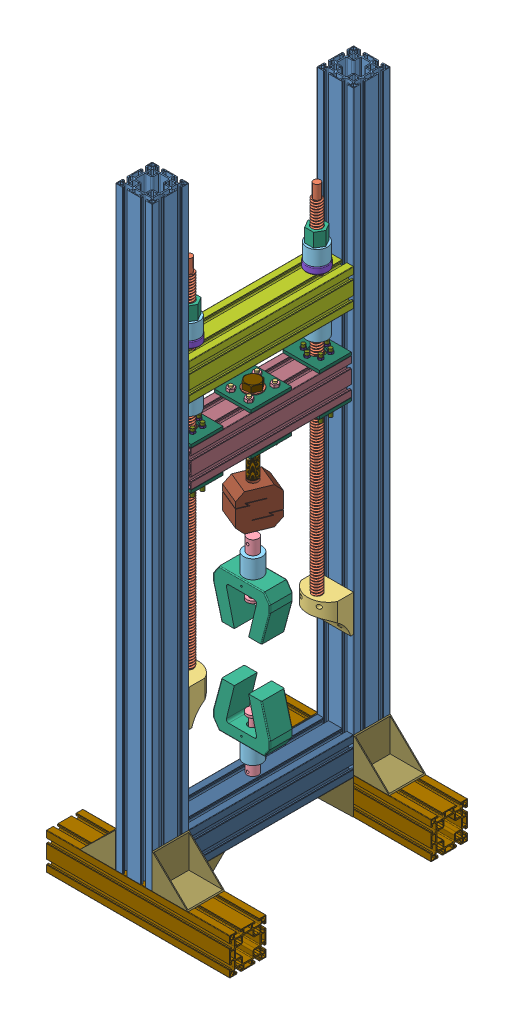
SolidWorks assembly NEWmodelUTM, configuration Default. Lengths in mm.
Overall size (400 1380 520).
55 component instances, 26 part files, 70 mates.
Components (placement in the parent):
- AL_profile780-1: AL_profile780 [Default] at (-40 0 -114.0799) size (80 1300 80)
- AL_profile780-2: AL_profile780 [Default] at (-40 0 325.9201) size (80 1300 80)
- leadscrew-1: leadscrew [Default] at (-40.1188 342.8251 -30.3753) x (0.717877 0 -0.69617) z (0 1 0) size (22.64 25.43 796)
- leadscrew-2: leadscrew [Default] at (-40.1188 342.8251 249.6247) x (0.179733 0 0.983715) z (0 1 0) size (22.64 25.43 796)
- bottomprintbase-1: bottomprintbase [Default] at (-40.1188 306.0641 289.6247) x (0 0 -1) z (1 0 0) size (60 80 80)
- Part2^NEWmodelUTM-1: Part2^NEWmodelUTM [Default] at origin (virtual)
- bottomprintbase-2: bottomprintbase [Default] at (-40.1188 306.0641 -70.3753) x (0 0 1) z (-1 0 0) size (60 80 80)
- gripper-1: gripper [Default] at (211.3531 265.4125 50.1916) x (-0.008195 0 0.999966) z (-0.999966 0 -0.008195) size (56.23 172.07 124.41)
  - grip_centre-1: grip_centre [Default] at (61.4916 134.6133 250.929) size (28.8 120.12 28.8)
  - grip_tightner-1: grip_tightner [Default] at (61.4916 140.8387 250.929) x (0.780296 0 -0.625411) z (0.625411 0 0.780296) size (40 39.84 40)
  - grip_jawbody-1: grip_jawbody [Default] at (36.4924 128.251 251.1338) x (0.999966 0 -0.008195) z (0.008195 0 0.999966) size (50 121.5 124)
- AL_profile360-1: AL_profile360 [Default] at (-40 926.1619 -70.3753) x (1 0 0) z (0 -1 0) size (80 360 80)
- ballbearing-1: ballbearing [Default] at (-40.1188 962.4573 -30.3753) x (0.823971 0 0.566631) z (-0.566631 0 0.823971) size (47.3 15 47.3)
- ballbearing-2: ballbearing [Default] at (-40.1188 962.4573 249.6247) x (0.997733 0 0.067299) z (-0.067299 0 0.997733) size (47.3 15 47.3)
- ballbearing-3: ballbearing [Default] at (-40.1188 867.4573 -30.3753) x (0.241118 0 -0.970496) z (0.970496 0 0.241118) size (47.3 15 47.3)
- ballbearing-4: ballbearing [Default] at (-40.1188 867.4573 249.6247) x (0.984243 0 0.176821) z (-0.176821 0 0.984243) size (47.3 15 47.3)
- AL_profile400legs-1: AL_profile400legs [Default] at (-231.1702 -40.1188 -114.0799) x (0 -1 0) z (0 0 1) size (80 400 80)
- AL_profile360base-1: AL_profile360base [Default] at (-40 39.3731 -70.3753) x (1 0 0) z (0 -1 0) size (80 360 80)
- AL_profile400legs-2: AL_profile400legs [Default] at (-231.1702 -43.7046 329.7436) x (0 0 1) z (0 1 0) size (80 400 80)
- gripper-2: gripper [Default] at (211.365 329.9394 169.0579) x (-0.008195 0 -0.999966) z (-0.999966 0 0.008195) size (56.23 172.07 124.41)
  - grip_centre-1: grip_centre [Default] at (61.4916 134.6133 250.929) size (28.8 120.12 28.8)
  - grip_tightner-1: grip_tightner [Default] at (61.4916 140.8387 250.929) x (0.780296 0 -0.625411) z (0.625411 0 0.780296) size (40 39.84 40)
  - grip_jawbody-1: grip_jawbody [Default] at (36.4924 128.251 251.1338) x (0.999966 0 -0.008195) z (0.008195 0 0.999966) size (50 121.5 124)
- Part3^NEWmodelUTM-1: Part3^NEWmodelUTM [Default] at origin (virtual)
- loadcell-1: loadcell [Default] at (-64.1199 589.8994 99.7422) x (0.380099 0 -0.924946) z (0.924946 0 0.380099) size (80 80 52)
- fixing brackets-1: fixing brackets [Default] at (-102.6188 22.5 -150.3753) x (0 1 0) z (1 0 0) size (75.67 80 78.01)
- fixing brackets-2: fixing brackets [Default] at (22.3812 22.5 -70.3753) x (0 1 0) z (-1 0 0) size (75.67 80 78.01)
- fixing brackets-3: fixing brackets [Default] at (22.3812 22.5 369.6247) x (0 1 0) z (-1 0 0) size (75.67 80 78.01)
- fixing brackets-4: fixing brackets [Default] at (-102.6188 22.5 289.6247) x (0 1 0) z (1 0 0) size (75.67 80 78.01)
- fixing brackets-5: fixing brackets [Default] at (-0.1188 -26.8315 -47.8753) x (0 -1 0) z (0 0 -1) size (75.67 80 78.01)
- fixing brackets-6: fixing brackets [Default] at (-80.1188 -26.8315 267.1247) x (0 -1 0) z (0 0 1) size (75.67 80 78.01)
- loading_beaM_assembly-1: loading_beaM_assembly [Default] at (-0.1307 882.4453 -65.3753) size (80.06 184 350)
  - AL_profile350-1: AL_profile350 [Default] at (-39.8812 -129.6235 350) x (1 0 0) z (0 1 0) size (80 350 80)
  - bearing for thread-1: bearing for thread [Default] at (-39.9881 -184.4189 315) size (55 44.2 55)
  - metal piece-1: metal piece [Default] at (-39.9406 -79.4189 175) x (1 0 0) z (0 -1 0) size (80 350 6.5)
  - side_threa_rods-1: side_threa_rods [Default] at (-39.9881 -199.4938 315) size (45.68 130 51.54)
  - side_threa_rods-2: side_threa_rods [Default] at (-39.9881 -199.4938 35) x (0.5 0 -0.866025) z (0.866025 0 0.5) size (45.68 130 51.54)
  - metal piece-3: metal piece [Default] at (-39.9406 -165.9189 175) x (1 0 0) z (0 -1 0) size (80 350 6.5)
  - bearing for thread-2: bearing for thread [Default] at (-39.9881 -184.4189 35) size (55 44.2 55)
  - nuts_7.8-1: nuts_7.8 [Default] at (-39.9881 -188.4189 315) size (47.17 4 54.47)
  - nuts_7.8-2: nuts_7.8 [Default] at (-39.9881 -188.4189 35) size (47.17 4 54.47)
  - nuts_7.8-3: nuts_7.8 [Default] at (-39.9881 -79.4189 35) size (47.17 4 54.47)
  - nuts_7.8-4: nuts_7.8 [Default] at (-39.9881 -79.4189 315) x (0.5 0 0.866025) z (-0.866025 0 0.5) size (47.17 4 54.47)
  - central_boltwithnut-1: central_boltwithnut [Default] at (-39.9406 -77.4189 175) x (-0.993893 0 0.11035) z (0.11035 0 0.993893) size (36.95 184 32)
  - central_nutforbolt-1: central_nutforbolt [Default] at (-39.9406 -175.2412 175) x (0.894237 0 -0.447594) z (0.447594 0 0.894237) size (41.05 18.73 38)
  - centralwaher-1: centralwaher [Default] at (-39.9406 -79.4189 175) size (40 2 40)
  - central4bolts-1: central4bolts [Default] at (-39.3156 -189.4938 174.9932) size (47.9 120 65.04)
  - M8nut-4: M8nut [Default] at (-59.8908 -79.4189 146.4879) size (55.9 6 70.85)
  - M8nut-5: M8nut [Default] at (-59.8908 -178.4189 146.4879) size (55.9 6 70.85)
- leadscrewcylindricalsupport-1: leadscrewcylindricalsupport [Default] at (-40.1188 977.4573 -30.3753) size (45 33 45)
- leadscrewcylindricalsupport-2: leadscrewcylindricalsupport [Default] at (-40.1188 977.4573 249.6247) x (0.961374 0 -0.275247) z (0.275247 0 0.961374) size (45 33 45)
- leadscrewcylindricalsupport-3: leadscrewcylindricalsupport [Default] at (-40.1188 834.4573 -30.3753) x (0.750227 0 -0.66118) z (0.66118 0 0.750227) size (45 33 45)
- leadscrewcylindricalsupport-4: leadscrewcylindricalsupport [Default] at (-40.1188 834.4573 249.6247) x (0.997856 0 -0.065451) z (0.065451 0 0.997856) size (45 33 45)
- leadscrew tightingnut-1: leadscrew tightingnut [Default] at (-40.1188 1010.4573 -30.3753) size (39.27 30 34.01)
- leadscrew tightingnut-2: leadscrew tightingnut [Default] at (-40.1188 1010.4573 249.6247) size (39.27 30 34.01)
Mates (geometry in assembly coordinates):
- Coincident1: coincident aligned: plane of AL_profile780-2 through (-80.1188 1300 325.9201) normal (-1 0 0); plane of AL_profile360-1 through (-80.1188 926.1619 289.6247) normal (-1 0 0)
- Coincident2: coincident anti-aligned: plane of AL_profile780-2 through (-40 1300 289.6247) normal (0 0 -1); plane of AL_profile360-1 through (-40 926.1619 289.6247) normal (0 0 1)
- Coincident3: coincident anti-aligned: plane of AL_profile780-1 through (-40 1300 -70.3753) normal (0 0 1); plane of AL_profile360-1 through (-40 926.1619 -70.3753) normal (0 0 -1)
- Coincident4: coincident aligned: plane of AL_profile780-1 through (-80.1188 1300 -114.0799) normal (-1 0 0); plane of AL_profile360-1 through (-80.1188 926.1619 289.6247) normal (-1 0 0)
- Coincident5: coincident anti-aligned: plane of AL_profile780-1 through (-40 1300 -70.3753) normal (0 0 1); plane of bottomprintbase-2 through (-40.1188 346.0641 -70.3753) normal (0 0 -1)
- Coincident6: coincident: plane of AL_profile780-1 through (-80.1188 1300 -114.0799) normal (-1 0 0); line of bottomprintbase-2 through (-80.1188 346.0641 -70.3753) axis (0 -1 0)
- Coincident7: coincident anti-aligned: plane of AL_profile780-2 through (-40 1300 289.6247) normal (0 0 -1); plane of bottomprintbase-1 through (-40.1188 346.0641 289.6247) normal (0 0 1)
- Coincident8: coincident aligned: plane of AL_profile780-2 through (-80.1188 1300 325.9201) normal (-1 0 0); plane of bottomprintbase-1 through (-80.1188 346.0641 289.6247) normal (-1 0 0)
- Coincident9: coincident aligned: plane of bottomprintbase-1 through (-40.1188 346.0641 289.6247) normal (0 1 0); plane of bottomprintbase-2 through (-40.1188 346.0641 -70.3753) normal (0 1 0)
- Concentric1: concentric aligned: circle of leadscrew-1; circle of AL_profile360-1
- Coincident13: coincident aligned: plane of leadscrew-1 through (-40.1188 1122.8251 -30.3753) normal (0 1 0); plane of leadscrew-2 through (-40.1188 1122.8251 249.6247) normal (0 1 0)
- Concentric2: concentric aligned: circle of leadscrew-2; circle of AL_profile360-1
- Concentric10: concentric aligned: circle of gripper-1/grip_centre-1; circle of loadcell-1
- Concentric11: concentric anti-aligned: circle of AL_profile360-1; circle of ballbearing-1
- Concentric12: concentric aligned: circle of AL_profile360-1; circle of ballbearing-2
- Concentric13: concentric aligned: circle of AL_profile360-1; circle of ballbearing-3
- Concentric14: concentric aligned: circle of AL_profile360-1; circle of ballbearing-4
- Parallel3: parallel anti-aligned: plane of AL_profile780-1 through (-80.1188 1300 -114.0799) normal (-1 0 0); plane of AL_profile400legs-1 through (168.8298 -40.1188 -114.0799) normal (1 0 0)
- Coincident22: coincident aligned: plane of AL_profile780-1 through (-40 1300 -70.3753) normal (0 0 1); plane of AL_profile400legs-1 through (168.8298 -40.1188 -70.3753) normal (0 0 1)
- Parallel4: parallel anti-aligned: plane of AL_profile400legs-1 through (168.8298 -40.1188 -70.3753) normal (0 0 1); plane of AL_profile400legs-2 through (168.8298 -43.7046 289.6247) normal (0 0 -1)
- Parallel5: parallel anti-aligned: plane of AL_profile400legs-1 through (-231.1702 -40.1188 -114.0799) normal (-1 0 0); plane of AL_profile400legs-2 through (168.8298 -43.7046 329.7436) normal (1 0 0)
- Coincident25: coincident anti-aligned: plane of AL_profile780-1 through (-40 0 -114.0799) normal (0 -1 0); plane of AL_profile400legs-1 through (168.8298 0 -114.0799) normal (0 1 0)
- Coincident27: coincident aligned: plane of AL_profile400legs-1 through (168.8298 -40.1188 -114.0799) normal (1 0 0); plane of AL_profile400legs-2 through (168.8298 -43.7046 329.7436) normal (1 0 0)
- Coincident28: coincident anti-aligned: plane of AL_profile360base-1 through (-40 39.3731 289.6247) normal (0 0 1); plane of AL_profile400legs-2 through (168.8298 -43.7046 289.6247) normal (0 0 -1)
- Coincident30: coincident anti-aligned: plane of AL_profile780-1 through (-40 1300 -70.3753) normal (0 0 1); plane of AL_profile360base-1 through (-40 39.3731 -70.3753) normal (0 0 -1)
- Coincident31: coincident aligned: plane of AL_profile780-2 through (-0.1188 1300 325.9201) normal (1 0 0); plane of AL_profile360base-1 through (-0.1188 39.3731 289.6247) normal (1 0 0)
- Concentric15: concentric anti-aligned: circle of AL_profile360base-1; circle of gripper-2/grip_centre-1
- Parallel6: parallel aligned: plane of gripper-1/grip_jawbody-1 through (-12.0328 423.7583 84.6247) normal (0 0 -1); plane of gripper-2/grip_jawbody-1 through (-12.0209 171.5936 84.6247) normal (0 0 -1)
- Coincident39: coincident anti-aligned: plane of AL_profile400legs-1 through (168.8298 0 -114.0799) normal (0 1 0); plane of fixing brackets-1 through (-80.1188 0 -70.3753) normal (0 -1 0)
- Coincident40: coincident anti-aligned: plane of AL_profile780-1 through (-80.1188 1300 -114.0799) normal (-1 0 0); plane of fixing brackets-1 through (-80.1188 0 -70.3753) normal (1 0 0)
- Coincident41: coincident aligned: plane of AL_profile780-1 through (-40 1300 -150.3753) normal (0 0 -1); plane of fixing brackets-1 through (-102.6188 22.5 -150.3753) normal (0 0 -1)
- Coincident42: coincident anti-aligned: plane of AL_profile780-1 through (-0.1188 1300 -114.0799) normal (1 0 0); plane of fixing brackets-2 through (-0.1188 0 -150.3753) normal (-1 0 0)
- Coincident43: coincident anti-aligned: plane of AL_profile400legs-1 through (168.8298 0 -114.0799) normal (0 1 0); plane of fixing brackets-2 through (-0.1188 0 -150.3753) normal (0 -1 0)
- Coincident44: coincident aligned: plane of AL_profile780-1 through (-40 1300 -150.3753) normal (0 0 -1); plane of fixing brackets-2 through (22.3812 22.5 -150.3753) normal (0 0 -1)
- Coincident45: coincident anti-aligned: plane of AL_profile780-2 through (-0.1188 1300 325.9201) normal (1 0 0); plane of fixing brackets-3 through (-0.1188 0 289.6247) normal (-1 0 0)
- Coincident46: coincident anti-aligned: plane of AL_profile400legs-2 through (168.8298 0 329.7436) normal (0 1 0); plane of fixing brackets-3 through (-0.1188 0 289.6247) normal (0 -1 0)
- Coincident47: coincident aligned: plane of AL_profile780-2 through (-40 1300 369.6247) normal (0 0 1); plane of fixing brackets-3 through (22.3812 22.5 369.6247) normal (0 0 1)
- Coincident51: coincident anti-aligned: plane of fixing brackets-4 through (-80.1188 0 369.6247) normal (0 -1 0); plane of AL_profile400legs-2 through (168.8298 0 329.7436) normal (0 1 0)
- Coincident52: coincident aligned: plane of AL_profile780-2 through (-40 1300 369.6247) normal (0 0 1); plane of fixing brackets-4 through (-102.6188 22.5 369.6247) normal (0 0 1)
- Coincident53: coincident anti-aligned: plane of AL_profile780-2 through (-80.1188 1300 325.9201) normal (-1 0 0); plane of fixing brackets-4 through (-80.1188 0 369.6247) normal (1 0 0)
- Coincident54: coincident anti-aligned: plane of AL_profile360base-1 through (-40 -4.3315 289.6247) normal (0 -1 0); plane of fixing brackets-5 through (-80.1188 -4.3315 -70.3753) normal (0 1 0)
- Coincident55: coincident anti-aligned: plane of AL_profile400legs-1 through (168.8298 -40.1188 -70.3753) normal (0 0 1); plane of fixing brackets-5 through (-80.1188 -4.3315 -70.3753) normal (0 0 -1)
- Coincident56: coincident aligned: plane of AL_profile360base-1 through (-80.1188 39.3731 289.6247) normal (-1 0 0); plane of fixing brackets-5 through (-80.1188 -26.8315 -47.8753) normal (-1 0 0)
- Coincident57: coincident anti-aligned: plane of AL_profile360base-1 through (-40 -4.3315 289.6247) normal (0 -1 0); plane of fixing brackets-6 through (-0.1188 -4.3315 289.6247) normal (0 1 0)
- Coincident58: coincident aligned: plane of AL_profile360base-1 through (-80.1188 39.3731 289.6247) normal (-1 0 0); plane of fixing brackets-6 through (-80.1188 -26.8315 267.1247) normal (-1 0 0)
- Coincident59: coincident anti-aligned: plane of AL_profile400legs-2 through (168.8298 -43.7046 289.6247) normal (0 0 -1); plane of fixing brackets-6 through (-0.1188 -4.3315 289.6247) normal (0 0 1)
- Coincident60: coincident: plane of AL_profile400legs-1 through (168.8298 -80 -114.0799) normal (0 -1 0); line of fixing brackets-5 through (-80.1188 -80 -70.3753) axis (1 0 0)
- Coincident61: coincident aligned: plane of AL_profile780-1 through (-40 1300 -114.0799) normal (0 1 0); plane of AL_profile780-2 through (-40 1300 325.9201) normal (0 1 0)
- Concentric16: concentric anti-aligned: circle of AL_profile360-1; circle of loading_beaM_assembly-1/metal piece-1
- Concentric17: concentric anti-aligned: circle of AL_profile360-1; circle of loading_beaM_assembly-1/metal piece-1
- Concentric18: concentric anti-aligned: cylinder of AL_profile360-1 through (-60.1188 902.4573 289.6247) axis (0 0 -1) radius 6.25; cylinder of AL_profile780-2 through (-60.1188 902.4573 289.6247) axis (0 0 1) radius 4
- Coincident64: coincident aligned: plane of gripper-1/grip_jawbody-1 through (-12.0328 423.7583 134.6247) normal (0 0 1); plane of gripper-2/grip_jawbody-1 through (-12.0209 171.5936 134.6247) normal (0 0 1)
- Coincident65: coincident anti-aligned: plane of AL_profile360-1 through (-40 962.4573 289.6247) normal (0 1 0); plane of ballbearing-2 through (-40.1188 962.4573 249.6247) normal (0 -1 0)
- Coincident66: coincident anti-aligned: plane of AL_profile360-1 through (-40 962.4573 289.6247) normal (0 1 0); plane of ballbearing-1 through (-40.1188 962.4573 -30.3753) normal (0 -1 0)
- Coincident67: coincident anti-aligned: plane of AL_profile360-1 through (-40 882.4573 289.6247) normal (0 -1 0); plane of ballbearing-3 through (-40.1188 882.4573 -30.3753) normal (0 1 0)
- Coincident68: coincident anti-aligned: plane of AL_profile360-1 through (-40 882.4573 289.6247) normal (0 -1 0); plane of ballbearing-4 through (-40.1188 882.4573 249.6247) normal (0 1 0)
- Concentric19: concentric aligned: circle of leadscrew-1; circle of leadscrewcylindricalsupport-1
- Coincident70: coincident anti-aligned: plane of ballbearing-1 through (-40.1188 977.4573 -30.3753) normal (0 1 0); plane of leadscrewcylindricalsupport-1 through (-40.1188 977.4573 -30.3753) normal (0 -1 0)
- Concentric21: concentric aligned: circle of leadscrew-2; circle of leadscrewcylindricalsupport-2
- Coincident71: coincident anti-aligned: plane of ballbearing-2 through (-40.1188 977.4573 249.6247) normal (0 1 0); plane of leadscrewcylindricalsupport-2 through (-40.1188 977.4573 249.6247) normal (0 -1 0)
- Concentric22: concentric aligned: circle of leadscrew-2; circle of leadscrewcylindricalsupport-4
- Concentric23: concentric aligned: circle of leadscrew-1; circle of leadscrewcylindricalsupport-3
- Coincident72: coincident aligned: plane of leadscrewcylindricalsupport-3 through (-40.1188 867.4573 -30.3753) normal (0 1 0); plane of leadscrewcylindricalsupport-4 through (-40.1188 867.4573 249.6247) normal (0 1 0)
- Coincident73: coincident anti-aligned: plane of ballbearing-3 through (-40.1188 867.4573 -30.3753) normal (0 -1 0); plane of leadscrewcylindricalsupport-3 through (-40.1188 867.4573 -30.3753) normal (0 1 0)
- Concentric24: concentric aligned: circle of leadscrew-1; circle of leadscrew tightingnut-1
- Concentric25: concentric anti-aligned: circle of leadscrew-2; cylinder of leadscrew tightingnut-2 through (-40.1188 1040.4573 249.6247) axis (0 -1 0) radius 11.5
- Coincident74: coincident aligned: plane of leadscrew tightingnut-1 through (-40.1188 1040.4573 -30.3753) normal (0 1 0); plane of leadscrew tightingnut-2 through (-40.1188 1040.4573 249.6247) normal (0 1 0)
- Coincident75: coincident anti-aligned: plane of leadscrewcylindricalsupport-1 through (-40.1188 1010.4573 -30.3753) normal (0 1 0); plane of leadscrew tightingnut-1 through (-40.1188 1010.4573 -30.3753) normal (0 -1 0)
- Concentric26: concentric aligned: circle of gripper-1/grip_centre-1; circle of loadcell-1
- Concentric27: concentric aligned: circle of loadcell-1; circle of loading_beaM_assembly-1/centralwaher-1
